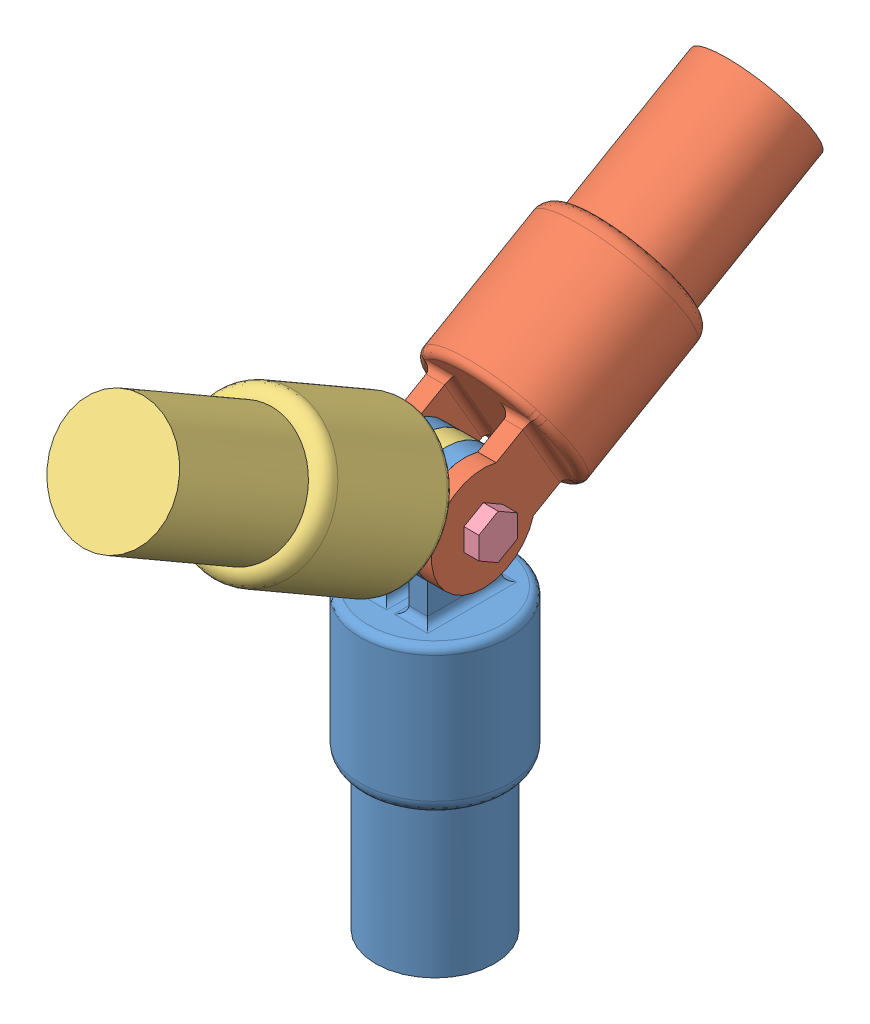
SolidWorks assembly Final Assembly, configuration Default. Lengths in mm.
Overall size (20 83.66 96.6).
4 component instances, 4 part files, 8 mates.
Components (placement in the parent):
- Joint Part 1.1-1: Joint Part 1.1 [Default] at (21.6042 0.4454 44.1228) size (20 57 20)
- Joint Part 1.2-1: Joint Part 1.2 [Default] at (21.6042 75.4454 0.8216) x (1 0 0) z (0 -0.866025 -0.5) size (20 57 20)
- Joint Part 1-1: Joint Part 1 [Default] at (21.6042 75.4454 87.4241) x (1 0 0) z (0 0.866025 -0.5) size (20 57 20)
- Joint Part 1.3-1: Joint Part 1.3 [Default] at (13.1042 50.4454 44.1228) x (0 -1 0) z (0 0 1) size (6 17 5.2)
Mates (geometry in assembly coordinates):
- Coincident4: coincident anti-aligned: cylinder of Joint Part 1.1-1 through (11.6042 50.4454 44.1228) axis (1 0 0) radius 2; circle of Joint Part 1-1
- Angle4: planar angle = 2.094395 rad aligned: plane of Joint Part 1-1 through (29.6042 57.2247 45.865) normal (0 0.866025 -0.5); plane of Joint Part 1.1-1 through (29.6042 45.547 49.1228) normal (0 0 1)
- Angle5: planar angle = 2.094395 rad aligned: plane of Joint Part 1.1-1 through (29.6042 45.547 49.1228) normal (0 0 1); plane of Joint Part 1.2-1 through (29.6042 48.5645 37.3807) normal (0 -0.866025 -0.5)
- Coincident6: coincident anti-aligned: plane of Joint Part 1.1-1 through (17.6042 50.4454 44.1228) normal (-1 0 0); plane of Joint Part 1.2-1 through (17.6042 42.3827 76.4182) normal (1 0 0)
- Concentric4: concentric aligned: cylinder of Joint Part 1.1-1 through (11.6042 50.4454 44.1228) axis (1 0 0) radius 2; cylinder of Joint Part 1.2-1 through (11.6042 50.4454 44.1228) axis (1 0 0) radius 2
- Coincident7: coincident anti-aligned: plane of Joint Part 1.1-1 through (20.1042 83.9454 34.236) normal (1 0 0); plane of Joint Part 1-1 through (20.1042 25.8831 21.3535) normal (-1 0 0)
- Concentric5: concentric anti-aligned: cylinder of Joint Part 1.2-1 through (11.6042 50.4454 44.1228) axis (1 0 0) radius 2; cylinder of Joint Part 1.3-1 through (28.1042 50.4454 44.1228) axis (-1 0 0) radius 2
- Coincident8: coincident anti-aligned: plane of Joint Part 1.2-1 through (15.1042 50.4454 44.1228) normal (-1 0 0); plane of Joint Part 1.3-1 through (15.1042 50.4454 44.1228) normal (1 0 0)
